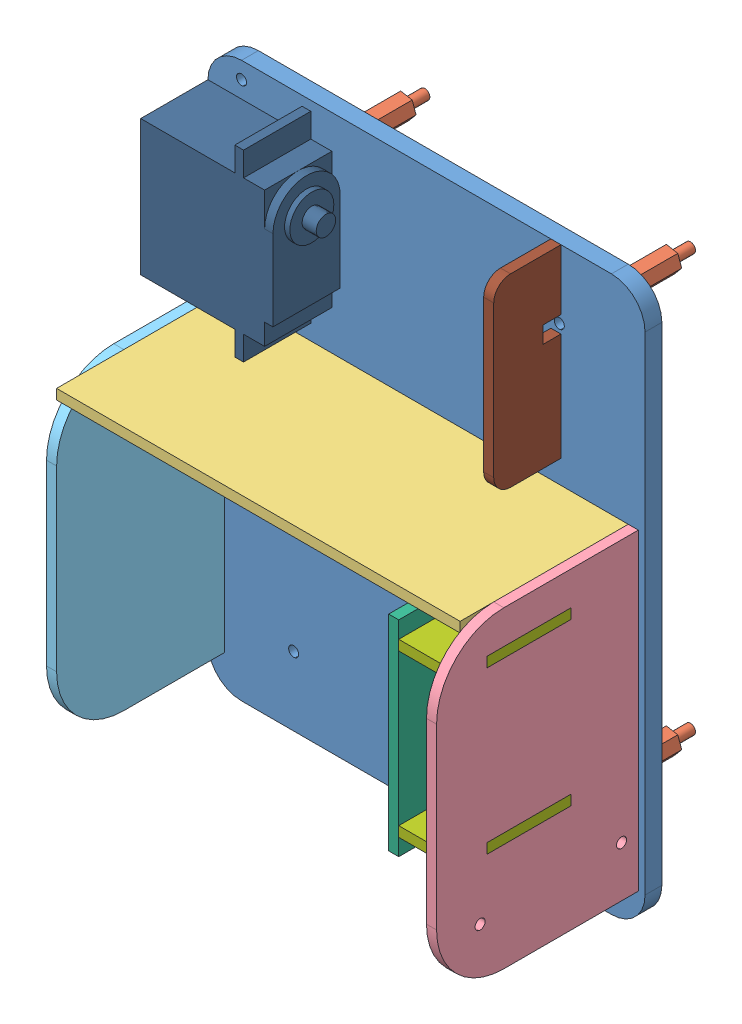
SolidWorks assembly Garra, configuration Valor predeterminado. Lengths in mm.
Overall size (130 165 99).
16 component instances, 11 part files, 32 mates.
Components (placement in the parent):
- Chassi-Cima-1: Chassi-Cima [Valor predeterminado] at (-175.2632 -27.1948 -23.6694) size (130 165 5)
- Standoff-Nylon-5: Standoff-Nylon [Valor predeterminado] at (-140.6723 87.6966 -51.6694) size (6.82 6.52 34)
- Standoff-Nylon-6: Standoff-Nylon [Valor predeterminado] at (-219.6723 87.6966 -51.6694) size (6.82 6.52 34)
- Standoff-Nylon-7: Standoff-Nylon [Valor predeterminado] at (-219.6723 -36.3034 -51.6694) size (6.82 6.52 34)
- Standoff-Nylon-8: Standoff-Nylon [Valor predeterminado] at (-140.6723 -36.3034 -51.6694) size (6.82 6.52 34)
- Cercado-Traseiro-2: Cercado-Traseiro [Valor predeterminado] at (-155.9895 39.4113 4.227) x (1 0 0) z (0 -1 0) size (120 55 3)
- Cercado-Direita-3: Cercado-Direita [Valor predeterminado] at (-109.4803 -16.6288 -7.2877) x (0 1 0) z (1 0 0) size (93 65 3)
- Cercado-Esquerda-2: Cercado-Esquerda [Valor predeterminado] at (-232.4803 -16.6288 -17.2877) x (0 1 0) z (1 0 0) size (93 55 3)
- Trava-Lateral-1: Trava-Lateral [Valor predeterminado] at (-64.4803 2.2199 2.9793) x (0 -1 0) z (-1 0 0) size (61 45 20.5)
  - Parede-1: Parede [Valor predeterminado] at (1.1301 17.3096 59.5) size (61 45 3)
  - Trava-1: Trava [Valor predeterminado] at (-24.1914 4.8096 92.7707) x (0 0 1) z (-1 0 0) size (20.5 45 3)
  - Trava-2: Trava [Valor predeterminado] at (23.8086 4.8096 92.7707) x (0 0 1) z (-1 0 0) size (20.5 45 3)
- Suporte-Servo-9g-1: Suporte-Servo-9g [Valor predeterminado] at (-128.1421 -23.4758 23.3806) x (0 1 0) z (1 0 0) size (13.25 52.05 17.5)
- Servo-9g-2: Servo-9g [Predeterminado] at (-115.7303 -29.0137 7.3306) x (1 0 0) z (0 -1 0) size (12.5 32.7 29.4)
- Servo-MG995-1: Servo-MG995 [Default] at (-234.4803 71.2813 -8.6694) x (0 -1 0) z (0 0 1) size (54.6 45.1 20)
- Mancal-1: Mancal [Valor predeterminado] at (-129.4803 43.4701 -20.0391) x (0 -1 0) z (-1 0 0) size (55 25 3)
Mates (geometry in assembly coordinates):
- Concêntrico4: concentric anti-aligned: circle of Chassi-Cima-1; circle of Standoff-Nylon-5
- Coincidente8: coincident anti-aligned: plane of Chassi-Cima-1 through (-224.4803 91.4113 -23.6694) normal (0 0 -1); plane of Standoff-Nylon-5 through (-140.6723 87.6966 -23.6694) normal (0 0 1)
- Concêntrico5: concentric anti-aligned: circle of Chassi-Cima-1; circle of Standoff-Nylon-6
- Coincidente10: coincident anti-aligned: plane of Chassi-Cima-1 through (-224.4803 91.4113 -23.6694) normal (0 0 -1); plane of Standoff-Nylon-6 through (-219.6723 87.6966 -23.6694) normal (0 0 1)
- Concêntrico6: concentric anti-aligned: circle of Chassi-Cima-1; circle of Standoff-Nylon-7
- Coincidente12: coincident anti-aligned: plane of Chassi-Cima-1 through (-224.4803 91.4113 -23.6694) normal (0 0 -1); plane of Standoff-Nylon-7 through (-219.6723 -36.3034 -23.6694) normal (0 0 1)
- Concêntrico7: concentric anti-aligned: circle of Chassi-Cima-1; circle of Standoff-Nylon-8
- Coincidente14: coincident anti-aligned: plane of Chassi-Cima-1 through (-224.4803 91.4113 -23.6694) normal (0 0 -1); plane of Standoff-Nylon-8 through (-140.6723 -36.3034 -23.6694) normal (0 0 1)
- Coincidente20: coincident anti-aligned: plane of Chassi-Cima-1 through (-156.9803 36.4113 -18.6694) normal (0 1 0); plane of Cercado-Traseiro-2 through (-155.9895 36.4113 4.227) normal (0 -1 0)
- Coincidente21: coincident anti-aligned: plane of Chassi-Cima-1 through (-139.4803 36.4113 -18.6694) normal (1 0 0); plane of Cercado-Traseiro-2 through (-139.4803 36.4113 -18.6694) normal (-1 0 0)
- Coincidente22: coincident aligned: plane of Chassi-Cima-1 through (-224.4803 91.4113 -23.6694) normal (0 0 -1); plane of Cercado-Traseiro-2 through (-139.4803 36.4113 -23.6694) normal (0 0 -1)
- Coincidente26: coincident anti-aligned: plane of Chassi-Cima-1 through (-106.4803 26.4113 -18.6694) normal (0 -1 0); plane of Cercado-Direita-3 through (-106.4803 26.4113 -18.6694) normal (0 1 0)
- Coincidente27: coincident anti-aligned: plane of Chassi-Cima-1 through (-106.4803 1.4113 -18.6694) normal (-1 0 0); plane of Cercado-Direita-3 through (-106.4803 -33.5887 21.3306) normal (1 0 0)
- Coincidente28: coincident aligned: plane of Chassi-Cima-1 through (-224.4803 91.4113 -23.6694) normal (0 0 -1); plane of Cercado-Direita-3 through (-106.4803 -53.5887 -23.6694) normal (0 0 -1)
- Coincidente32: coincident anti-aligned: plane of Chassi-Cima-1 through (-232.4803 26.4113 -18.6694) normal (0 -1 0); plane of Cercado-Esquerda-2 through (-229.4803 26.4113 -18.6694) normal (0 1 0)
- Coincidente33: coincident anti-aligned: plane of Chassi-Cima-1 through (-229.4803 26.4113 -18.6694) normal (-1 0 0); plane of Cercado-Esquerda-2 through (-229.4803 -33.5887 11.3306) normal (1 0 0)
- Coincidente34: coincident aligned: plane of Chassi-Cima-1 through (-224.4803 91.4113 -23.6694) normal (0 0 -1); plane of Cercado-Esquerda-2 through (-229.4803 1.4113 -23.6694) normal (0 0 -1)
- Coincidente35: coincident anti-aligned: plane of Cercado-Direita-3 through (-116.4803 -18.5887 26.3306) normal (0 -1 0); plane of Trava-Lateral-1/Trava-2 through (-157.2511 -18.5887 7.789) normal (0 1 0)
- Coincidente36: coincident anti-aligned: plane of Cercado-Direita-3 through (-116.4803 -21.5887 1.3306) normal (0 0 1); plane of Trava-Lateral-1/Trava-2 through (-109.4803 -18.5887 1.3306) normal (0 0 -1)
- Coincidente37: coincident aligned: plane of Cercado-Direita-3 through (-106.4803 -33.5887 21.3306) normal (1 0 0); plane of Trava-Lateral-1/Trava-2 through (-106.4803 -18.5887 1.3306) normal (1 0 0)
- Concêntrico8: concentric anti-aligned: circle of Cercado-Direita-3; circle of Suporte-Servo-9g-1
- Concêntrico9: concentric anti-aligned: circle of Cercado-Direita-3; circle of Suporte-Servo-9g-1
- Coincidente40: coincident anti-aligned: plane of Cercado-Direita-3 through (-109.4803 -33.5887 21.3306) normal (-1 0 0); plane of Suporte-Servo-9g-1 through (-109.4803 -45.2137 18.7306) normal (1 0 0)
- Coincidente44: coincident anti-aligned: plane of Suporte-Servo-9g-1 through (-109.4803 -31.9637 -4.0194) normal (0 0 1); plane of Servo-9g-2 through (-121.9803 -52.0137 -4.0194) normal (0 0 -1)
- Coincidente45: coincident anti-aligned: plane of Suporte-Servo-9g-1 through (-121.9803 -23.4758 23.3806) normal (1 0 0); plane of Servo-9g-2 through (-121.9803 -52.0137 -4.0194) normal (-1 0 0)
- Coincidente46: coincident anti-aligned: plane of Suporte-Servo-9g-1 through (-121.9803 -45.2137 18.7306) normal (0 -1 0); plane of Servo-9g-2 through (-109.4803 -45.2137 18.6806) normal (0 1 0)
- Coincidente47: coincident aligned: plane of Chassi-Cima-1 through (-234.4803 -53.5887 -18.6694) normal (-1 0 0); plane of Servo-MG995-1 through (-234.4803 71.2813 -8.6694) normal (-1 0 0)
- Coincidente48: coincident anti-aligned: plane of Chassi-Cima-1 through (-224.4803 91.4113 -18.6694) normal (0 0 1); plane of Servo-MG995-1 through (-197.6203 91.4113 -18.6694) normal (0 0 -1)
- Distância1: distance = 10 mm aligned: plane of Servo-MG995-1 through (-197.6203 91.4113 1.3306) normal (0 1 0); plane of Chassi-Cima-1 through (-224.4803 101.4113 -18.6694) normal (0 1 0)
- Coincidente50: coincident anti-aligned: plane of Chassi-Cima-1 through (-129.4803 76.4113 -13.6694) normal (0 -1 0); plane of Mancal-1 through (-132.4803 76.4113 -18.6694) normal (0 1 0)
- Coincidente51: coincident anti-aligned: plane of Chassi-Cima-1 through (-132.4803 76.4113 -13.6694) normal (1 0 0); plane of Mancal-1 through (-132.4803 96.4113 -3.6694) normal (-1 0 0)
- Coincidente52: coincident aligned: plane of Chassi-Cima-1 through (-224.4803 91.4113 -23.6694) normal (0 0 -1); plane of Mancal-1 through (-132.4803 76.4113 -23.6694) normal (0 0 -1)
